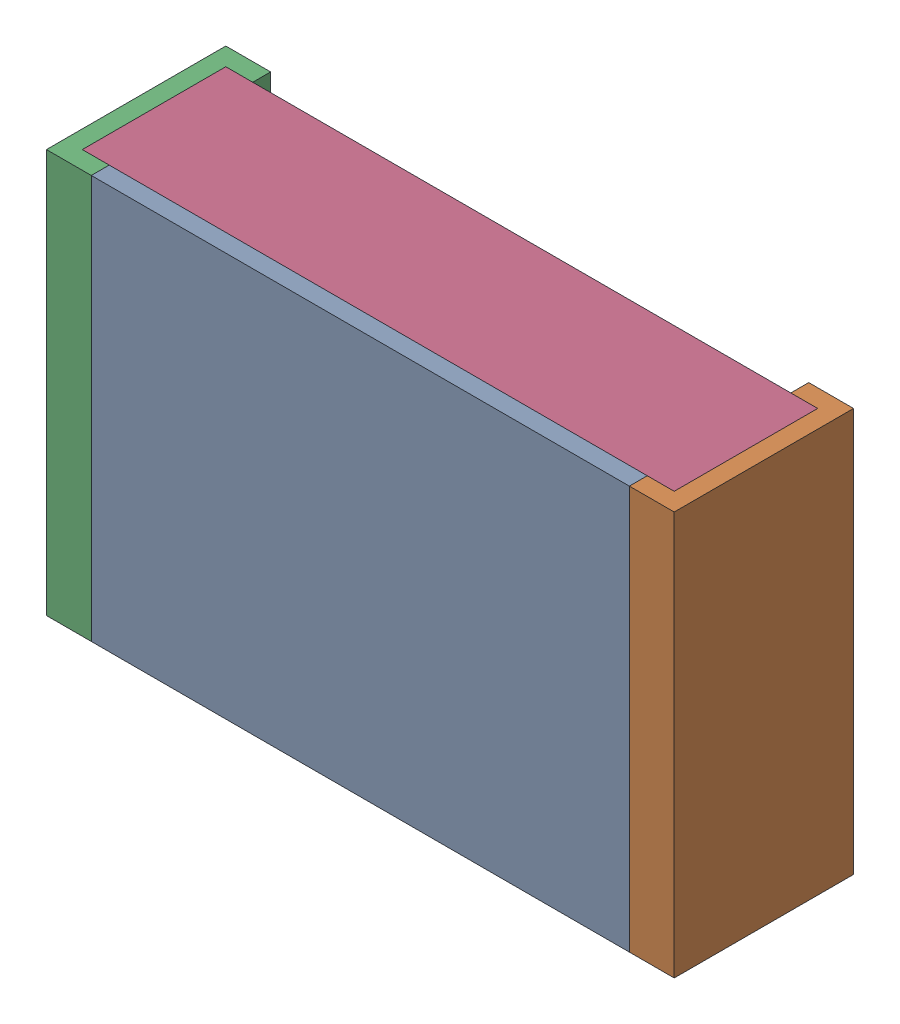
SolidWorks assembly RESC2012X06N.step-3, configuration По умолчанию. Lengths in mm.
Overall size (2.1 1.35 0.6).
4 component instances, 3 part files, 0 mates.
Components (placement in the parent):
- RESC2012X06N.step-Part-1-1: RESC2012X06N.step-Part-1 [По умолчанию] at (-0.9 -0.675 0.54) size (1.8 1.35 0.06)
- RESC2012X06N.step-Part-2-1: RESC2012X06N.step-Part-2 [По умолчанию] at (1.05 0.675 0) x (-1 0 0) z (0 0 1) size (0.15 1.35 0.6)
- RESC2012X06N.step-Part-2-2: RESC2012X06N.step-Part-2 [По умолчанию] at (-1.05 -0.675 0) size (0.15 1.35 0.6)
- RESC2012X06N.step-Part-3-1: RESC2012X06N.step-Part-3 [По умолчанию] at (-1.05 -0.675 0) size (1.98 1.35 0.48)
